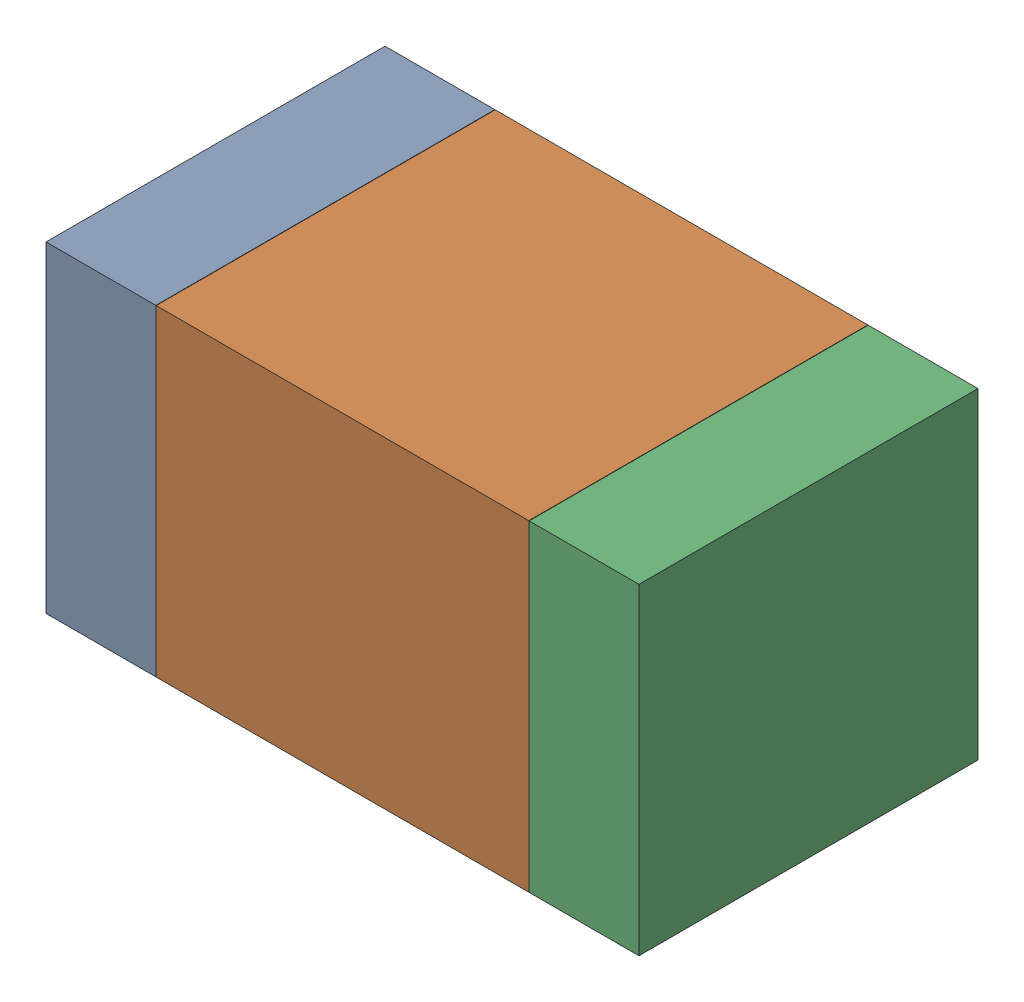
SolidWorks assembly R34, configuration Default. Lengths in mm.
Overall size (1.75 0.95 1).
6 component instances, 2 part files, 0 mates.
Components (placement in the parent):
- 6575498272-1: 6575498272 [Default] at (5.5105 38.227 0) size (0.32 0.95 1)
  - Extruded_8-1: Extruded_8 [Default] at origin size (0.32 0.95 1)
- 6575498112-1: 6575498112 [Default] at (6.223 38.227 0) size (1.1 0.95 1)
  - Extruded_9-1: Extruded_9 [Default] at origin size (1.1 0.95 1)
- 6575498272-2: 6575498272 [Default] at (6.9355 38.227 0) size (0.32 0.95 1)
  - Extruded_8-1: Extruded_8 [Default] at origin size (0.32 0.95 1)
